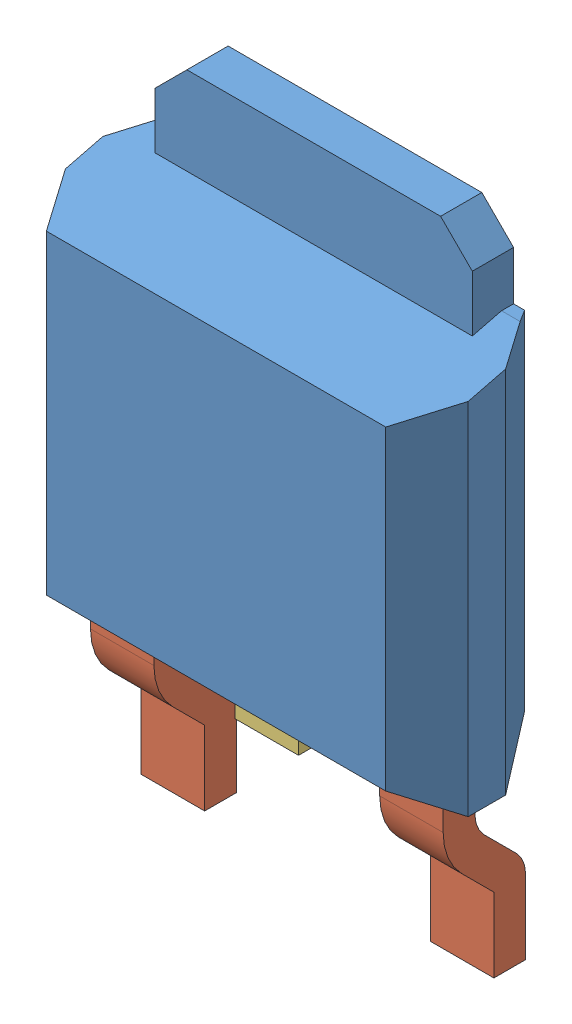
SolidWorks assembly Assemblage1, configuration Défaut. Lengths in mm.
Overall size (6.35 10.04 2.19).
4 component instances, 3 part files, 9 mates.
Components (placement in the parent):
- Q1_boitier-1: Q1_boitier [Défaut] at (-49.4045 4.9439 -1.095) size (6.35 7.24 2.19)
- Q1_Pin-1: Q1_Pin [Défaut] at (-49.0095 2.1439 -0.505) x (0 0 -1) z (1 0 0) size (1.3 2.8 1)
- Q1_Pin2-1: Q1_Pin2 [Défaut] at (-45.7295 5.2439 2.6813) x (0 1 0) z (-1 0 0) size (0.5 0.41 1)
- Q1_Pin-2: Q1_Pin [Défaut] at (-44.4495 2.1439 -0.505) x (0 0 -1) z (1 0 0) size (1.3 2.8 1)
Mates (geometry in assembly coordinates):
- Coïncidente1: coincident anti-aligned: plane of Q1_boitier-1 through (-49.4045 4.9439 1.095) normal (0 -1 0); plane of Q1_Pin-1 through (-48.0095 4.9439 0.295) normal (0 1 0)
- Coïncidente2: coincident aligned: line of Q1_boitier-1 through (-43.0545 4.9439 0.295) axis (-1 0 0); line of Q1_Pin-1 through (-48.0095 4.9439 0.295) axis (-1 0 0)
- Coïncidente3: coincident anti-aligned: plane of Q1_boitier-1 through (-49.4045 4.9439 1.095) normal (0 -1 0); plane of Q1_Pin2-1 through (-46.7295 4.9439 -0.1187) normal (0 1 0)
- Coïncidente4: coincident: moEndPointRef_w of Q1_boitier-1; moEndPointRef_w of Q1_Pin2-1
- Parallèle1: parallel aligned: plane of Q1_boitier-1 through (-49.4045 4.9439 1.095) normal (-1 0 0); plane of Q1_Pin2-1 through (-46.7295 4.9439 -0.1187) normal (-1 0 0)
- Distance1: distance = 1.28 mm anti-aligned: plane of Q1_Pin2-1 through (-46.7295 4.9439 -0.1187) normal (-1 0 0); plane of Q1_Pin-1 through (-48.0095 3.3159 -0.505) normal (1 0 0)
- Coïncidente7: coincident anti-aligned: plane of Q1_boitier-1 through (-49.4045 4.9439 1.095) normal (0 -1 0); plane of Q1_Pin-2 through (-43.4495 4.9439 0.295) normal (0 1 0)
- Coïncidente8: coincident aligned: line of Q1_boitier-1 through (-43.0545 4.9439 0.295) axis (-1 0 0); line of Q1_Pin-2 through (-43.4495 4.9439 0.295) axis (-1 0 0)
- Distance3: distance = 2.28 mm aligned: plane of Q1_Pin2-1 through (-45.7295 4.9439 -0.1187) normal (1 0 0); plane of Q1_Pin-2 through (-43.4495 3.3159 -0.505) normal (1 0 0)
